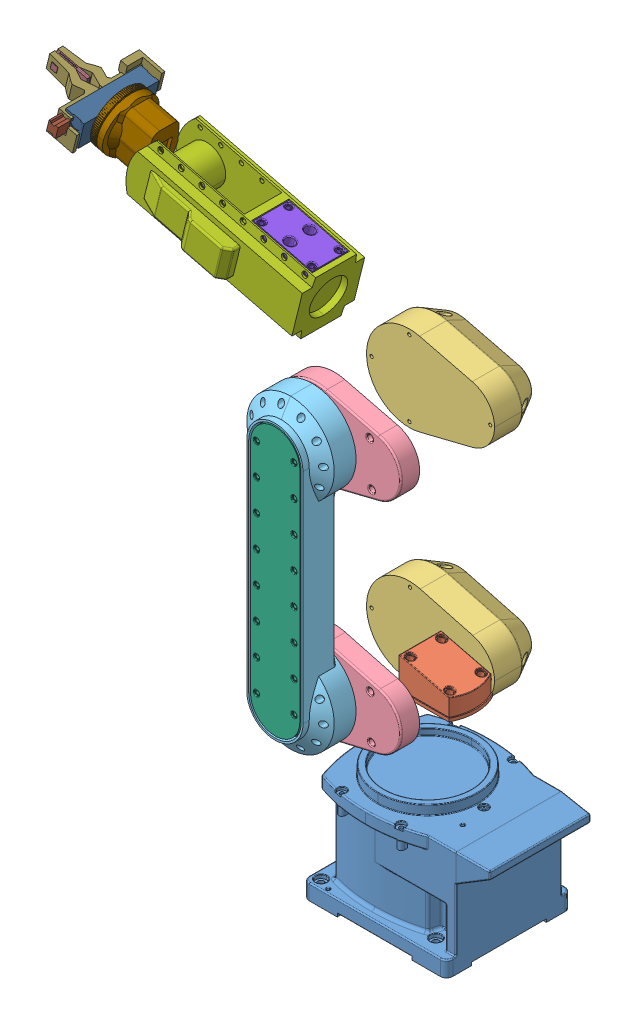
SolidWorks assembly movable step 5, configuration Default. Lengths in mm.
Overall size (786.84 890.65 303.13).
20 component instances, 16 part files, 57 mates.
Components (placement in the parent):
- Base.step-1: Base.step [Default] at (50.4601 21.8888 234.5287) size (280 185 200)
- Joint_1.step-1: Joint_1.step [Default] at (68.2167 333.4398 234.5287) size (242.75 189 160) (hidden)
- Joint_1_top_cap.step-1: Joint_1_top_cap.step [Default] at (70.5148 316.8888 234.5287) x (1 0 0) z (0 1 0) size (91.2 70 52.34)
- Part3.step-1: Part3.step [Default] at (63.4179 21.928 234.5287) x (0.999815 -0.016322 -0.010154) z (0.010153 -0.000166 0.999948) size (205.53 137 83.39)
- Part4.step-1: Part4.step [Default] at (63.4179 21.928 234.5287) x (0.999815 -0.016322 -0.010154) z (0.010153 -0.000166 0.999948) size (205.37 137 45.97)
- Joint_2.step-1: Joint_2.step [Default] at (-21.7667 647.378 238.6434) x (0 -0.999953 -0.009698) z (0.003009 -0.009698 0.999948) size (490.3 140.11 64.56)
- joint_2_cap.step-1: joint_2_cap.step [Default] at (-275.8903 144.2787 234.5287) x (0.296333 -0.955031 -0.010154) z (0.003009 -0.009698 0.999948) size (415.27 184.72 18.75)
- Part3.step-2: Part3.step [Default] at (68.4534 373.4102 234.5287) x (0.999948 0.000764 -0.010154) z (0.010154 0.000008 0.999948) size (205.53 137 83.39)
- Part4.step-2: Part4.step [Default] at (68.4534 373.4102 234.5287) x (0.999948 0.000764 -0.010154) z (0.010154 0.000008 0.999948) size (205.37 137 45.97)
- Part5.step-1: Part5.step [Default] at (24.1084 630.1919 238.2942) x (0.970756 -0.239852 -0.010154) z (0.009858 -0.002436 0.999948) size (270.42 212 122.27) (hidden)
- Joint_3_front^industry_robot_arm_3.step-1: Joint_3_front^industry_robot_arm_3.step [Default] at (-224.4166 709.3124 234.7907) x (0.970807 -0.239864 0) z (0 0 1) size (280 99.67 120)
- Joint_3_top_cap^industry_robot_arm_3.step-1: Joint_3_top_cap^industry_robot_arm_3.step [Default] at (295.0467 179.5597 234.7907) x (0.970807 -0.239864 0) z (0 0 1) size (97 20 57)
- joint_4^industry_robot_arm_3.step-1: joint_4^industry_robot_arm_3.step [Default] at (-554.8076 967.2397 234.7907) x (-0.970807 0.239864 0) z (0 0 1) size (126.86 92 60) (hidden)
- joint_4_front^industry_robot_arm_3.step-1: joint_4_front^industry_robot_arm_3.step [Default] at (-401.6939 796.0726 78.0925) x (0 0 -1) z (0.970807 -0.239864 0) size (88 89.06 70)
- joint_4_super_front^industry_robot_arm_3.step-1: joint_4_super_front^industry_robot_arm_3.step [Default] at (-447.1433 778.8854 -119.2569) x (0 0 1) z (-0.970807 0.239864 0) size (120 40 40)
- joint_4_super_front_middle^industry_robot_arm_3.step-1: joint_4_super_front_middle^industry_robot_arm_3.step [Default] at (-467.3861 778.2523 -180.2963) x (0 0 1) z (-0.970807 0.239864 0) size (160 18 25)
- Gripper_left^industry_robot_arm_3.step-1: Gripper_left^industry_robot_arm_3.step [Default] at (410.0528 507.9058 373.8777) x (0.970807 -0.239864 0) z (0 0 1) size (105.79 39 65)
- Gripper_left^industry_robot_arm_3.step-2: Gripper_left^industry_robot_arm_3.step [Default] at (477.8722 782.3926 90.6237) x (0.970807 -0.239864 0) z (0 0 -1) size (105.79 39 65)
- Gripper_right_grip^industry_robot_arm_3.step-1: Gripper_right_grip^industry_robot_arm_3.step [Default] at (542.6596 1119.0264 2282.2226) x (-0.954279 0.23578 -0.183739) z (-0.178375 0.044072 0.982975) size (52.87 24 20.92)
- Gripper_right_grip^industry_robot_arm_3.step-2: Gripper_right_grip^industry_robot_arm_3.step [Default] at (310.607 179.8353 -1817.7211) x (-0.954279 0.23578 0.183739) z (-0.178375 0.044072 -0.982975) size (52.87 24 20.92)
Mates (geometry in assembly coordinates):
- Concentric1: concentric aligned: cylinder of Base.step-1 through (68.2167 206.8888 234.5287) axis (0 -1 0) radius 80; cylinder of Joint_1.step-1 through (68.2167 222.8888 234.5287) axis (0 -1 0) radius 69
- Coincident1: coincident anti-aligned: plane of Base.step-1 through (68.2167 196.8888 234.5287) normal (0 1 0); plane of Joint_1.step-1 through (68.2167 196.8888 234.5287) normal (0 -1 0)
- Parallel1: parallel aligned: plane of Base.step-1 through (198.2167 111.8888 319.5287) normal (0 0 1); plane of Joint_1.step-1 through (68.2167 333.4398 274.5287) normal (0 0 1)
- Coincident2: coincident anti-aligned: plane of Joint_1.step-1 through (68.2167 316.8888 234.5287) normal (0 1 0); plane of Joint_1_top_cap.step-1 through (70.5148 316.8888 234.5287) normal (0 -1 0)
- Concentric3: concentric aligned: cylinder of Joint_1.step-1 through (68.2167 385.8888 234.5287) axis (0 -1 0) radius 75; cylinder of Joint_1_top_cap.step-1 through (68.2167 470.6805 234.5287) axis (0 -1 0) radius 75.4393
- Parallel2: parallel anti-aligned: plane of Joint_1.step-1 through (52.0118 385.8888 269.5287) normal (1 0 0); plane of Joint_1_top_cap.step-1 through (55.8099 470.6805 201.0287) normal (-1 0 0)
- Coincident3: coincident anti-aligned: plane of Joint_1.step-1 through (68.2167 333.4398 174.5287) normal (0 0 -1); plane of Part3.step-1 through (68.2167 315.8888 174.5287) normal (0 0 1)
- Concentric4: concentric anti-aligned: cylinder of Joint_1.step-1 through (68.2167 315.8888 274.5287) axis (0 0 -1) radius 48.4134; cylinder of Part3.step-1 through (68.2167 315.8888 94.5287) axis (0 0 1) radius 46.9225
- Tangent1: tangent aligned: cylinder of Joint_1.step-1 through (-21.7787 315.8888 274.5287) axis (0 0 -1) radius 70; cylinder of Part3.step-1 through (-21.4511 317.3526 94.5287) axis (0 0 1) radius 68.5
- Coincident4: coincident anti-aligned: plane of Joint_1.step-1 through (68.2167 333.4398 294.5287) normal (0 0 1); plane of Part4.step-1 through (68.2167 315.8888 294.5287) normal (0 0 -1)
- Concentric6: concentric aligned: cylinder of Joint_1.step-1 through (68.2167 315.8888 274.5287) axis (0 0 -1) radius 48.4134; cylinder of Part4.step-1 through (68.2167 315.8888 324.5287) axis (0 0 -1) radius 46.9225
- Tangent2: tangent aligned: cylinder of Joint_1.step-1 through (-21.7787 315.8888 274.5287) axis (0 0 -1) radius 70; cylinder of Part4.step-1 through (-21.4511 317.3526 324.5287) axis (0 0 -1) radius 68.5
- Coincident5: coincident anti-aligned: plane of Part4.step-1 through (-21.7667 317.3577 329.5287) normal (0 0 1); plane of Joint_2.step-1 through (-21.7667 317.3577 329.5287) normal (0 0 -1)
- Concentric7: concentric aligned: cylinder of Part4.step-1 through (-21.7667 317.3577 339.5287) axis (0 0 -1) radius 30; cylinder of Joint_2.step-1 through (-21.7667 317.3577 339.5287) axis (0 0 -1) radius 30
- Parallel3: parallel aligned: plane of Base.step-1 through (198.2167 46.8888 134.5287) normal (1 0 0); plane of Joint_2.step-1 through (23.2333 667.3413 339.5287) normal (1 0 0)
- Concentric8: concentric anti-aligned: cylinder of Joint_2.step-1 through (-21.7667 317.3577 374.5287) axis (0 0 1) radius 42; cylinder of joint_2_cap.step-1 through (-21.7667 317.3577 389.0687) axis (0 0 -1) radius 39.5
- Coincident6: coincident anti-aligned: plane of Joint_2.step-1 through (-21.7667 667.3413 374.5287) normal (0 0 1); plane of joint_2_cap.step-1 through (-21.7667 317.3577 374.5287) normal (0 0 -1)
- Concentric9: concentric anti-aligned: cylinder of Joint_2.step-1 through (-21.7667 667.3413 374.5287) axis (0 0 1) radius 42; cylinder of joint_2_cap.step-1 through (-21.7667 667.3413 389.0687) axis (0 0 -1) radius 39.5
- Coincident7: coincident anti-aligned: plane of Joint_2.step-1 through (-21.7667 667.3413 329.5287) normal (0 0 -1); plane of Part4.step-2 through (-21.7667 667.3413 329.5287) normal (0 0 1)
- Concentric10: concentric aligned: cylinder of Joint_2.step-1 through (-21.7667 667.3413 339.5287) axis (0 0 -1) radius 30; cylinder of Part4.step-2 through (-21.7667 667.3413 339.5287) axis (0 0 -1) radius 30
- Concentric11: concentric anti-aligned: cylinder of Part4.step-2 through (68.2286 667.4101 324.5287) axis (0 0 -1) radius 46.9225; cylinder of Part5.step-1 through (68.2286 667.4101 174.5287) axis (0 0 1) radius 46.9225
- Coincident8: coincident anti-aligned: plane of Part4.step-2 through (68.2286 667.4101 294.5287) normal (0 0 -1); plane of Part5.step-1 through (68.2286 667.4101 294.5287) normal (0 0 1)
- Concentric12: concentric anti-aligned: cylinder of Part4.step-2 through (-21.4511 667.3415 324.5287) axis (0 0 -1) radius 68.5; cylinder of Part5.step-1 through (-21.4511 667.3415 174.5287) axis (0 0 1) radius 68.5
- Coincident9: coincident anti-aligned: plane of Part3.step-2 through (68.2286 667.4101 174.5287) normal (0 0 1); plane of Part5.step-1 through (68.2286 667.4101 174.5287) normal (0 0 -1)
- Concentric13: concentric aligned: cylinder of Part3.step-2 through (-21.4511 667.3415 94.5287) axis (0 0 1) radius 68.5; cylinder of Part5.step-1 through (-21.4511 667.3415 174.5287) axis (0 0 1) radius 68.5
- Tangent3: tangent aligned: cylinder of Part3.step-2 through (68.2286 667.4101 94.5287) axis (0 0 1) radius 46.9225; cylinder of Part5.step-1 through (68.2286 667.4101 174.5287) axis (0 0 1) radius 46.9225
- Parallel4: parallel aligned: plane of Joint_1.step-1 through (75.7423 363.8986 274.5287) normal (0.239864 0.970807 0); plane of Part5.step-1 through (-25.6032 811.0323 179.5287) normal (0.239864 0.970807 0)
- Coincident10: coincident anti-aligned: plane of Part5.step-1 through (-102.9867 727.1449 184.5287) normal (-0.970807 0.239864 0); plane of Joint_3_front^industry_robot_arm_3.step-1 through (-79.0405 824.0629 284.7907) normal (0.970807 -0.239864 0)
- Concentric14: concentric aligned: cylinder of Part5.step-1 through (-100.7016 778.0838 234.5287) axis (0.970807 -0.239864 0) radius 30; cylinder of Joint_3_front^industry_robot_arm_3.step-1 through (-100.7016 778.0838 234.5287) axis (0.970807 -0.239864 0) radius 30
- Distance1: distance = 1.5 mm anti-aligned: plane of Joint_3_top_cap^industry_robot_arm_3.step-1 through (-182.4314 849.6084 206.2907) normal (-0.970807 0.239864 0); plane of Joint_3_front^industry_robot_arm_3.step-1 through (-188.6849 830.5521 204.7907) normal (0.970807 -0.239864 0)
- Distance3: distance = 1.5 mm anti-aligned: plane of Joint_3_top_cap^industry_robot_arm_3.step-1 through (-182.4314 849.6084 263.2907) normal (0 0 1); plane of Joint_3_front^industry_robot_arm_3.step-1 through (-188.6849 830.5521 264.7907) normal (0 0 -1)
- Coincident13: coincident anti-aligned: plane of Joint_3_front^industry_robot_arm_3.step-1 through (-194.1287 831.8972 234.7907) normal (0.239864 0.970807 0); plane of Joint_3_top_cap^industry_robot_arm_3.step-1 through (418.8064 680.455 234.7907) normal (-0.239864 -0.970807 0)
- Parallel5: parallel aligned: plane of Part5.step-1 through (-102.9867 727.1449 284.5287) normal (0 0 1); plane of Joint_3_front^industry_robot_arm_3.step-1 through (-224.4166 709.3124 284.7907) normal (0 0 1)
- Concentric15: concentric anti-aligned: cylinder of Joint_3_front^industry_robot_arm_3.step-1 through (-315.373 832.7636 264.7907) axis (0 0 -1) radius 30; cylinder of joint_4^industry_robot_arm_3.step-1 through (-315.373 832.7636 204.7907) axis (0 0 1) radius 30
- Coincident14: coincident anti-aligned: plane of Joint_3_front^industry_robot_arm_3.step-1 through (-495.1524 824.2125 264.7907) normal (0 0 -1); plane of joint_4^industry_robot_arm_3.step-1 through (-554.8076 967.2397 264.7907) normal (0 0 1)
- Coincident15: coincident anti-aligned: plane of joint_4^industry_robot_arm_3.step-1 through (-346.3749 915.7408 234.7907) normal (-0.970807 0.239864 0); plane of joint_4_front^industry_robot_arm_3.step-1 through (-377.4237 790.076 78.0925) normal (0.970807 -0.239864 0)
- Coincident19: coincident anti-aligned: plane of joint_4^industry_robot_arm_3.step-1 through (-360.3154 859.3189 249.7907) normal (0.239864 0.970807 0); plane of joint_4_front^industry_robot_arm_3.step-1 through (-360.3154 859.3189 249.7907) normal (-0.239864 -0.970807 0)
- Coincident20: coincident anti-aligned: plane of joint_4^industry_robot_arm_3.step-1 through (-367.5113 830.1947 249.7907) normal (0 0 1); plane of joint_4_front^industry_robot_arm_3.step-1 through (-360.3154 859.3189 249.7907) normal (0 0 -1)
- Coincident21: coincident anti-aligned: plane of joint_4_front^industry_robot_arm_3.step-1 through (-430.8181 803.2685 78.0925) normal (-0.970807 0.239864 0); plane of joint_4_super_front^industry_robot_arm_3.step-1 through (-437.4353 776.4867 -119.2569) normal (0.970807 -0.239864 0)
- Coincident22: coincident anti-aligned: plane of joint_4_front^industry_robot_arm_3.step-1 through (-413.7098 872.5114 219.7907) normal (0 0 1); plane of joint_4_super_front^industry_robot_arm_3.step-1 through (-420.9057 843.3872 219.7907) normal (0 0 -1)
- Coincident23: coincident anti-aligned: plane of joint_4_front^industry_robot_arm_3.step-1 through (-413.7098 872.5114 219.7907) normal (-0.239864 -0.970807 0); plane of joint_4_super_front^industry_robot_arm_3.step-1 through (-413.7098 872.5114 249.7907) normal (0.239864 0.970807 0)
- Coincident24: coincident anti-aligned: plane of joint_4_super_front^industry_robot_arm_3.step-1 through (-456.366 781.1641 -119.2569) normal (-0.970807 0.239864 0); plane of joint_4_super_front_middle^industry_robot_arm_3.step-1 through (-457.6781 775.8536 -180.2963) normal (0.970807 -0.239864 0)
- Coincident25: coincident anti-aligned: plane of joint_4_super_front^industry_robot_arm_3.step-1 through (-435.0391 867.4807 239.7907) normal (0 0 -1); plane of joint_4_super_front_middle^industry_robot_arm_3.step-1 through (-435.0391 867.4807 239.7907) normal (0 0 1)
- Coincident26: coincident anti-aligned: plane of joint_4_super_front^industry_robot_arm_3.step-1 through (-435.0391 867.4807 229.7907) normal (-0.239864 -0.970807 0); plane of joint_4_super_front_middle^industry_robot_arm_3.step-1 through (-435.0391 867.4807 239.7907) normal (0.239864 0.970807 0)
- Coincident27: coincident anti-aligned: plane of joint_4_super_front_middle^industry_robot_arm_3.step-1 through (-481.9482 781.8502 -180.2963) normal (-0.970807 0.239864 0); plane of Gripper_left^industry_robot_arm_3.step-1 through (-458.3498 877.3605 294.7907) normal (0.970807 -0.239864 0)
- Coincident28: coincident anti-aligned: plane of joint_4_super_front_middle^industry_robot_arm_3.step-1 through (-458.2395 861.3671 154.7907) normal (-0.239864 -0.970807 0); plane of Gripper_left^industry_robot_arm_3.step-1 through (-458.2395 861.3671 294.7907) normal (0.239864 0.970807 0)
- Parallel6: parallel aligned: plane of Joint_3_top_cap^industry_robot_arm_3.step-1 through (423.6037 699.8711 234.7907) normal (0.239864 0.970807 0); plane of joint_4^industry_robot_arm_3.step-1 through (-228.114 852.4067 264.7907) normal (0.239864 0.970807 0)
- Coincident29: coincident anti-aligned: plane of joint_4_super_front_middle^industry_robot_arm_3.step-1 through (-481.9482 781.8502 -180.2963) normal (-0.970807 0.239864 0); plane of Gripper_left^industry_robot_arm_3.step-2 through (-462.6674 859.886 169.7107) normal (0.970807 -0.239864 0)
- Coincident30: coincident anti-aligned: plane of joint_4_super_front_middle^industry_robot_arm_3.step-1 through (-458.2395 861.3671 154.7907) normal (-0.239864 -0.970807 0); plane of Gripper_left^industry_robot_arm_3.step-2 through (-453.3854 860.1678 169.7107) normal (0.239864 0.970807 0)
- Coincident31: coincident anti-aligned: plane of Gripper_left^industry_robot_arm_3.step-1 through (-501.1855 866.3127 234.7907) normal (0 0 -1); plane of Gripper_right_grip^industry_robot_arm_3.step-1 through (542.6596 1119.0264 234.7907) normal (0 0 1)
- Coincident34: coincident anti-aligned: plane of Gripper_left^industry_robot_arm_3.step-2 through (-495.4288 889.6121 229.7107) normal (0 0 1); plane of Gripper_right_grip^industry_robot_arm_3.step-2 through (310.607 179.8353 229.7107) normal (0 0 -1)
- Coincident35: coincident anti-aligned: plane of Gripper_left^industry_robot_arm_3.step-1 through (-524.1532 889.4987 244.7907) normal (0.970807 -0.239864 0); plane of Gripper_right_grip^industry_robot_arm_3.step-1 through (-526.5518 879.7907 244.7907) normal (-0.970807 0.239864 0)
- Coincident36: coincident anti-aligned: plane of Gripper_left^industry_robot_arm_3.step-1 through (-514.4451 887.1001 244.7907) normal (-0.239864 -0.970807 0); plane of Gripper_right_grip^industry_robot_arm_3.step-1 through (-514.4451 887.1001 244.7907) normal (0.239864 0.970807 0)
- Coincident37: coincident anti-aligned: plane of Gripper_left^industry_robot_arm_3.step-2 through (-516.8438 877.392 219.7107) normal (0.239864 0.970807 0); plane of Gripper_right_grip^industry_robot_arm_3.step-2 through (-516.8438 877.392 219.7107) normal (-0.239864 -0.970807 0)
- Coincident38: coincident anti-aligned: plane of Gripper_left^industry_robot_arm_3.step-2 through (-516.8438 877.392 219.7107) normal (-0.970807 0.239864 0); plane of Gripper_right_grip^industry_robot_arm_3.step-2 through (-514.4451 887.1001 219.7107) normal (0.970807 -0.239864 0)
- Coincident39: coincident anti-aligned: plane of Gripper_right_grip^industry_robot_arm_3.step-1 through (542.6596 1119.0264 232.2507) normal (0 0 -1); plane of Gripper_right_grip^industry_robot_arm_3.step-2 through (310.607 179.8353 232.2507) normal (0 0 1)
- Coincident40: coincident anti-aligned: plane of joint_4_super_front^industry_robot_arm_3.step-1 through (-451.3427 886.96 294.7907) normal (0 0 1); plane of Gripper_left^industry_robot_arm_3.step-1 through (410.0528 507.9058 294.7907) normal (0 0 -1)
